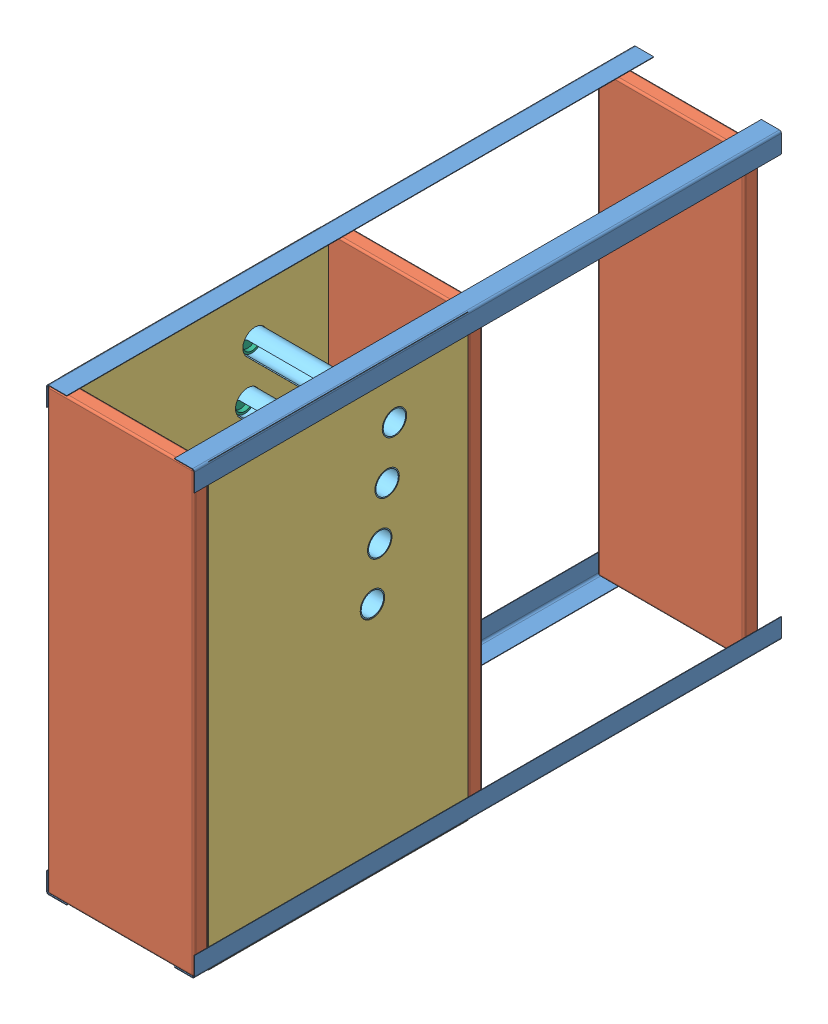
SolidWorks assembly Assem1, configuration Default. Lengths in mm.
Overall size (307 902 1200).
18 component instances, 6 part files, 46 mates.
Components (placement in the parent):
- Part1-1: Part1 [Default] at (351.6144 620.781 352.0871) size (41 41 1200)
- Part1-2: Part1 [Default] at (651.6144 1519.781 352.0871) x (-1 0 0) z (0 0 1) size (41 41 1200)
- Part1-3: Part1 [Default] at (651.6144 620.781 1552.0871) x (-1 0 0) z (0 0 -1) size (41 41 1200)
- Part1-4: Part1 [Default] at (351.6144 1520.781 352.0871) x (0 -1 0) z (0 0 1) size (41 41 1200)
- Part2-1: Part2 [Default] at (351.6144 1520.781 1522.0871) x (0 -1 0) z (0 0 1) size (900 300 30)
- Part2-2: Part2 [Default] at (651.6144 620.781 962.0871) x (0 1 0) z (0 0 1) size (900 300 30)
- Part2-3: Part2 [Default] at (651.6144 620.781 397.0871) x (0 1 0) z (0 0 1) size (900 300 30)
- Part3-2: Part3 [Default] at (351.6144 620.781 992.0871) x (0 1 0) z (1 0 0) size (900 530 15)
- Part4-1: Part4 [Default] at (366.6144 1019.781 992.0871) x (1 0 0) z (0 -1 0) size (270 530 15)
- Part3-3: Part3 [Default] at (636.6144 619.781 992.0871) x (0 1 0) z (1 0 0) size (900 530 15)
- Part5-1: Part5 [Default] at (351.6144 1399.781 1142.0871) x (0 1 0) z (1 0 0) size (50 50 300)
- Part5-5: Part5 [Default] at (351.6144 1199.781 1172.0871) x (0 1 0) z (1 0 0) size (50 50 300)
- Part5-6: Part5 [Default] at (351.6144 1299.781 1157.0871) x (0 1 0) z (1 0 0) size (50 50 300)
- Part5-7: Part5 [Default] at (351.6144 1100.781 1187.0871) x (0 1 0) z (1 0 0) size (50 50 300)
- Part6-1: Part6 [Default] at (345.6144 1399.781 1142.0871) x (0 1 0) z (1 0 0) size (56 56 15)
- Part6-2: Part6 [Default] at (345.6144 1299.781 1157.0871) x (0 0.964903 -0.262608) z (1 0 0) size (56 56 15)
- Part6-3: Part6 [Default] at (345.6144 1199.781 1172.0871) x (0 0.976645 0.21486) z (1 0 0) size (56 56 15)
- Part6-4: Part6 [Default] at (345.6144 1100.781 1187.0871) x (0 1 0) z (1 0 0) size (56 56 15)
Mates (geometry in assembly coordinates):
- Coincident1: coincident: plane of assembly; plane of assembly; plane of Part1-4 through (391.6144 1520.781 1552.0871) normal (0 -1 0); plane of Part2-1 through (351.6144 1520.781 1552.0871) normal (0 1 0)
- Coincident2: coincident: plane of assembly; plane of assembly; plane of Part1-4 through (351.6144 1516.781 1552.0871) normal (1 0 0); plane of Part2-1 through (351.6144 1520.781 1552.0871) normal (-1 0 0)
- Coincident4: coincident: plane of assembly; plane of assembly; plane of Part1-3 through (651.6144 660.781 352.0871) normal (-1 0 0); plane of Part2-1 through (651.6144 1520.781 1552.0871) normal (1 0 0)
- Coincident5: coincident: plane of assembly; plane of assembly; plane of Part1-3 through (647.6144 620.781 352.0871) normal (0 1 0); plane of Part2-1 through (351.6144 620.781 1552.0871) normal (0 -1 0)
- Parallel1: parallel: plane of assembly; plane of assembly; plane of Part1-2 through (611.6144 1520.781 1552.0871) normal (0 1 0); plane of Part1-3 through (611.6144 619.781 352.0871) normal (0 -1 0)
- Coincident8: coincident: plane of assembly; plane of assembly; plane of Part1-2 through (651.6144 1479.781 1552.0871) normal (-1 0 0); plane of Part2-1 through (651.6144 1520.781 1552.0871) normal (1 0 0)
- Coincident9: coincident: plane of assembly; plane of assembly; plane of Part1-2 through (611.6144 1520.781 1552.0871) normal (0 1 0); plane of Part2-1 through (351.6144 1520.781 1552.0871) normal (0 1 0)
- Coincident11: coincident: plane of assembly; plane of assembly; plane of Part2-1 through (351.6144 1520.781 1552.0871) normal (0 0 1); plane of Part1-3 through (648.6144 623.781 1552.0871) normal (0 0 1)
- Coincident12: coincident: plane of assembly; plane of assembly; plane of Part1-4 through (354.6144 1517.781 1552.0871) normal (0 0 1); plane of Part2-1 through (351.6144 1520.781 1552.0871) normal (0 0 1)
- Coincident13: coincident: plane of assembly; plane of assembly; plane of Part1-2 through (648.6144 1516.781 1552.0871) normal (0 0 1); plane of Part2-1 through (351.6144 1520.781 1552.0871) normal (0 0 1)
- Coincident15: coincident: plane of assembly; plane of assembly; plane of Part1-1 through (351.6144 660.781 1552.0871) normal (1 0 0); plane of Part2-1 through (351.6144 1520.781 1552.0871) normal (-1 0 0)
- Coincident16: coincident: plane of assembly; plane of assembly; plane of Part1-1 through (355.6144 620.781 1552.0871) normal (0 1 0); plane of Part2-1 through (351.6144 620.781 1552.0871) normal (0 -1 0)
- Coincident17: coincident: plane of assembly; plane of assembly; plane of Part1-1 through (354.6144 623.781 1552.0871) normal (0 0 1); plane of Part2-1 through (351.6144 1520.781 1552.0871) normal (0 0 1)
- Parallel2: parallel: plane of assembly; plane of assembly; plane of Part2-1 through (651.6144 1520.781 1552.0871) normal (1 0 0); plane of Part2-2 through (351.6144 620.781 992.0871) normal (-1 0 0)
- Coincident20: coincident: plane of assembly; plane of assembly; plane of Part2-1 through (651.6144 1520.781 1552.0871) normal (1 0 0); plane of Part2-2 through (651.6144 620.781 992.0871) normal (1 0 0)
- Coincident21: coincident: plane of assembly; plane of assembly; plane of Part2-1 through (351.6144 1520.781 1552.0871) normal (0 1 0); plane of Part2-2 through (651.6144 1520.781 992.0871) normal (0 1 0)
- Parallel3: parallel: plane of assembly; plane of assembly; plane of Part2-2 through (651.6144 620.781 992.0871) normal (1 0 0); plane of Part2-3 through (351.6144 620.781 427.0871) normal (-1 0 0)
- Coincident23: coincident: plane of assembly; plane of assembly; plane of Part2-1 through (651.6144 1520.781 1552.0871) normal (1 0 0); plane of Part2-3 through (651.6144 620.781 427.0871) normal (1 0 0)
- Coincident24: coincident: plane of assembly; plane of assembly; plane of Part2-1 through (351.6144 1520.781 1552.0871) normal (0 1 0); plane of Part2-3 through (651.6144 1520.781 427.0871) normal (0 1 0)
- Distance1: distance = 45 mm: plane of assembly; plane of assembly; plane of Part1-2 through (648.6144 1516.781 352.0871) normal (0 0 -1); plane of Part2-3 through (651.6144 620.781 397.0871) normal (0 0 -1)
- Distance2: distance = 530 mm: plane of assembly; plane of assembly; plane of Part2-1 through (351.6144 1520.781 1522.0871) normal (0 0 -1); plane of Part2-2 through (651.6144 620.781 992.0871) normal (0 0 1)
- Coincident31: coincident: plane of assembly; plane of assembly; plane of Part1-1 through (351.6144 660.781 1552.0871) normal (1 0 0); plane of Part3-2 through (351.6144 620.781 992.0871) normal (-1 0 0)
- Coincident32: coincident: plane of assembly; plane of assembly; plane of Part2-2 through (651.6144 620.781 992.0871) normal (0 0 1); plane of Part3-2 through (366.6144 620.781 992.0871) normal (0 0 -1)
- Coincident33: coincident: plane of assembly; plane of assembly; plane of Part1-4 through (391.6144 1520.781 1552.0871) normal (0 -1 0); plane of Part3-2 through (366.6144 1520.781 992.0871) normal (0 1 0)
- Coincident35: coincident: plane of assembly; plane of assembly; plane of Part2-2 through (651.6144 620.781 992.0871) normal (0 0 1); plane of Part4-1 through (366.6144 1004.781 992.0871) normal (0 0 -1)
- Distance3: distance = 500 mm: plane of assembly; plane of assembly; plane of Part4-1 through (366.6144 1019.781 992.0871) normal (0 1 0); plane of Part1-2 through (647.6144 1519.781 1552.0871) normal (0 -1 0)
- Coincident37: coincident: plane of assembly; plane of assembly; plane of Part2-2 through (651.6144 620.781 992.0871) normal (0 0 1); plane of Part3-3 through (651.6144 619.781 992.0871) normal (0 0 -1)
- Coincident38: coincident: plane of assembly; plane of assembly; plane of Part1-2 through (647.6144 1519.781 1552.0871) normal (0 -1 0); plane of Part3-3 through (651.6144 1519.781 992.0871) normal (0 1 0)
- Coincident39: coincident: plane of assembly; plane of assembly; plane of Part1-2 through (651.6144 1479.781 1552.0871) normal (-1 0 0); plane of Part3-3 through (651.6144 619.781 992.0871) normal (1 0 0)
- Concentric1: concentric: cylinder of assembly; cylinder of assembly; cylinder of Part3-3 through (651.6144 1399.781 1142.0871) axis (-1 0 0) radius 25; cylinder of Part5-1 through (651.6144 1399.781 1142.0871) axis (-1 0 0) radius 23
- Coincident40: coincident: plane of assembly; plane of assembly; plane of Part3-3 through (651.6144 619.781 992.0871) normal (1 0 0); plane of Part5-1 through (651.6144 1399.781 1142.0871) normal (1 0 0)
- Parallel4: parallel: plane of assembly; plane of assembly; plane of Part4-1 through (366.6144 1019.781 992.0871) normal (0 1 0); plane of Part5-1 through (371.6144 1384.781 1141.0871) normal (0 1 0)
- Concentric2: concentric: cylinder of assembly; cylinder of assembly; cylinder of Part3-3 through (651.6144 1299.781 1157.0871) axis (-1 0 0) radius 25; cylinder of Part5-6 through (651.6144 1299.781 1157.0871) axis (-1 0 0) radius 23
- Concentric3: concentric: cylinder of assembly; cylinder of assembly; cylinder of Part3-3 through (651.6144 1199.781 1172.0871) axis (-1 0 0) radius 25; cylinder of Part5-5 through (651.6144 1199.781 1172.0871) axis (-1 0 0) radius 23
- Concentric4: concentric: cylinder of assembly; cylinder of assembly; cylinder of Part3-2 through (366.6144 1100.781 1187.0871) axis (-1 0 0) radius 25; cylinder of Part5-7 through (651.6144 1100.781 1187.0871) axis (-1 0 0) radius 23
- Coincident42: coincident: plane of assembly; plane of assembly; plane of Part3-2 through (351.6144 620.781 992.0871) normal (-1 0 0); plane of Part5-7 through (351.6144 1100.781 1187.0871) normal (-1 0 0)
- Coincident43: coincident: plane of assembly; circle of assembly; plane of Part3-3 through (651.6144 619.781 992.0871) normal (1 0 0); circle of Part5-5
- Coincident44: coincident: plane of assembly; plane of assembly; plane of Part3-3 through (651.6144 619.781 992.0871) normal (1 0 0); plane of Part5-6 through (651.6144 1299.781 1157.0871) normal (1 0 0)
- Concentric5: concentric: cylinder of assembly; cylinder of assembly; cylinder of Part5-1 through (651.6144 1399.781 1142.0871) axis (-1 0 0) radius 23; cylinder of Part6-1 through (351.6144 1399.781 1142.0871) axis (-1 0 0) radius 28
- Coincident46: coincident: plane of assembly; plane of assembly; plane of Part3-2 through (351.6144 620.781 992.0871) normal (-1 0 0); plane of Part6-1 through (351.6144 1399.781 1142.0871) normal (1 0 0)
- Concentric6: concentric: cylinder of assembly; cylinder of assembly; cylinder of Part5-6 through (651.6144 1299.781 1157.0871) axis (-1 0 0) radius 23; cylinder of Part6-2 through (351.6144 1299.781 1157.0871) axis (-1 0 0) radius 28
- Coincident47: coincident: plane of assembly; plane of assembly; plane of Part3-2 through (351.6144 620.781 992.0871) normal (-1 0 0); plane of Part6-2 through (351.6144 1299.781 1157.0871) normal (1 0 0)
- Concentric7: concentric: cylinder of assembly; cylinder of assembly; cylinder of Part5-5 through (651.6144 1199.781 1172.0871) axis (-1 0 0) radius 23; cylinder of Part6-3 through (351.6144 1199.781 1172.0871) axis (-1 0 0) radius 28
- Coincident48: coincident: plane of assembly; plane of assembly; plane of Part3-2 through (351.6144 620.781 992.0871) normal (-1 0 0); plane of Part6-3 through (351.6144 1199.781 1172.0871) normal (1 0 0)
- Coincident49: coincident: plane of assembly; plane of assembly; plane of Part3-2 through (351.6144 620.781 992.0871) normal (-1 0 0); plane of Part6-4 through (351.6144 1100.781 1187.0871) normal (1 0 0)
- Concentric8: concentric: cylinder of assembly; cylinder of assembly; cylinder of Part5-7 through (651.6144 1100.781 1187.0871) axis (-1 0 0) radius 23; cylinder of Part6-4 through (351.6144 1100.781 1187.0871) axis (-1 0 0) radius 28
